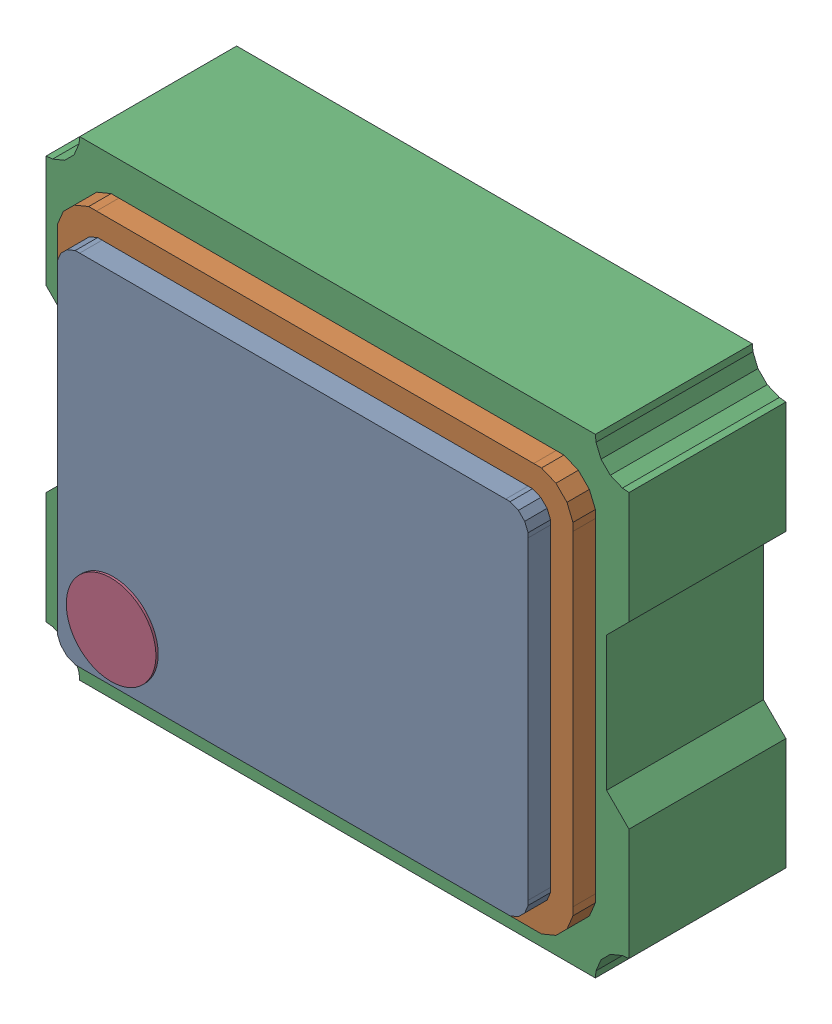
SolidWorks assembly X1, configuration Default. Lengths in mm.
Overall size (2.6 2.1 0.91).
8 component instances, 4 part files, 0 mates.
Components (placement in the parent):
- 1737246152-1: 1737246152 [Default] at (5.25 35.8 0.8) size (2.1 1.6 0.1)
  - Extruded-12-1: Extruded-12 [Default] at origin size (2.1 1.6 0.1)
- 1737246288-1: 1737246288 [Default] at (5.25 35.8 0.7) size (2.3 1.8 0.1)
  - Extruded-13-1: Extruded-13 [Default] at origin size (2.3 1.8 0.1)
- 1737246424-1: 1737246424 [Default] at (5.25 35.8 0) size (2.6 2.1 0.7)
  - Extruded-14-1: Extruded-14 [Default] at origin size (2.6 2.1 0.7)
- 981747792-1: 981747792 [Default] at (4.4501 35.2251 0.9) x (1 0 0) z (0 0 1) size (0.4 0.4 0.01)
  - Cylinder-1: Cylinder [Default] at origin size (0.4 0.4 0.01)
